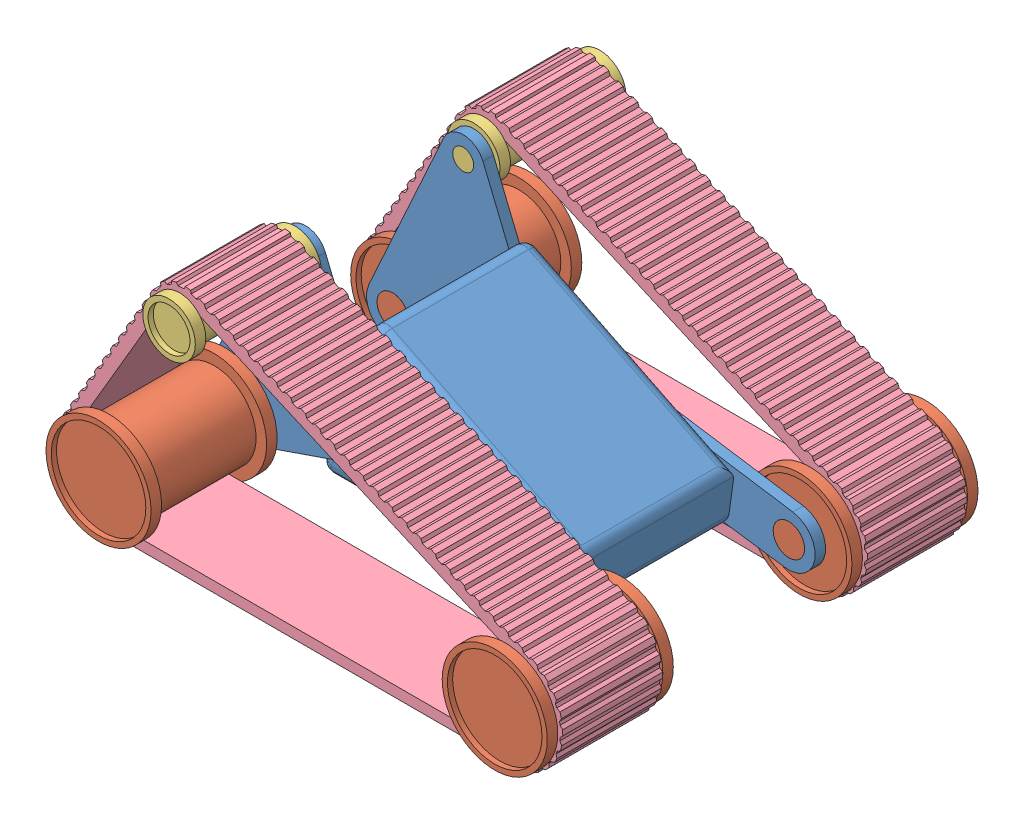
SolidWorks assembly E3_S5_E1, configuration Predeterminado. Lengths in mm.
Overall size (96.38 48.33 82).
9 component instances, 4 part files, 8 mates.
Components (placement in the parent):
- E3_S5_P1-1: E3_S5_P1 [Predeterminado] at (2.8381 -16.306 -90.9846) size (85.42 40.78 34)
- E3_S5_P2-1: E3_S5_P2 [Predeterminado] at (-72.5819 -16.306 -124.9846) size (20 20 26)
- E3_S5_P2-2: E3_S5_P2 [Predeterminado] at (2.8381 -16.306 -124.9846) size (20 20 26)
- E3_S5_P3-1: E3_S5_P3 [Predeterminado] at (-59.1611 15.4027 -124.9846) size (10 10 26)
- E3_S5_P4-2: E3_S5_P4 [Predeterminado] at (-72.5819 -16.306 -144.4846) size (96.38 48.33 19)
- E3_S5_P4-3: E3_S5_P4 [Predeterminado] at (-72.5819 -16.306 -86.4846) size (96.38 48.33 19)
- E3_S5_P3-2: E3_S5_P3 [Predeterminado] at (-59.1611 15.4027 -86.9846) x (-1 0 0) z (0 0 -1) size (10 10 26)
- E3_S5_P2-3: E3_S5_P2 [Predeterminado] at (-72.5819 -16.306 -86.9846) x (-1 0 0) z (0 0 -1) size (20 20 26)
- E3_S5_P2-4: E3_S5_P2 [Predeterminado] at (2.8381 -16.306 -86.9846) x (-1 0 0) z (0 0 -1) size (20 20 26)
Mates (geometry in assembly coordinates):
- Coincidente12: coincident: plane of E3_S5_P1-1 through (2.8381 -16.306 -120.9846) normal (0 0 1); plane of E3_S5_P2-2 through (2.8381 -16.306 -120.9846) normal (0 0 1)
- Coincidente13: coincident: cylinder of E3_S5_P1-1 through (2.8381 -16.306 -120.9846) axis (0 0 -1) radius 3; circle of E3_S5_P2-2
- Concéntrica14: concentric: cylinder of E3_S5_P1-1 through (-72.5819 -16.306 -120.9846) axis (0 0 -1) radius 3; cylinder of E3_S5_P2-1 through (-72.5819 -16.306 -120.9846) axis (0 0 -1) radius 3
- Coincidente16: coincident: plane of E3_S5_P1-1 through (2.8381 -16.306 -120.9846) normal (0 0 1); plane of E3_S5_P2-1 through (-72.5819 -16.306 -120.9846) normal (0 0 1)
- Concéntrica15: concentric: cylinder of E3_S5_P1-1 through (-59.1611 15.4027 -120.9846) axis (0 0 -1) radius 2; cylinder of E3_S5_P3-1 through (-59.1611 15.4027 -120.9846) axis (0 0 -1) radius 2
- Coincidente17: coincident: plane of E3_S5_P1-1 through (2.8381 -16.306 -120.9846) normal (0 0 1); plane of E3_S5_P3-1 through (-59.1611 15.4027 -120.9846) normal (0 0 1)
- Concéntrica16: concentric: cylinder of E3_S5_P4-2 through (-72.5819 -16.306 -125.4846) axis (0 0 -1) radius 8; cylinder of E3_S5_P2-1 through (-72.5819 -16.306 -134.9846) axis (0 0 1) radius 8
- Distancia1: distance = 0.5 mm: plane of E3_S5_P4-2 through (-58.9079 14.9893 -144.4846) normal (0 0 -1); plane of E3_S5_P2-1 through (-72.5819 -16.306 -144.9846) normal (0 0 1)
